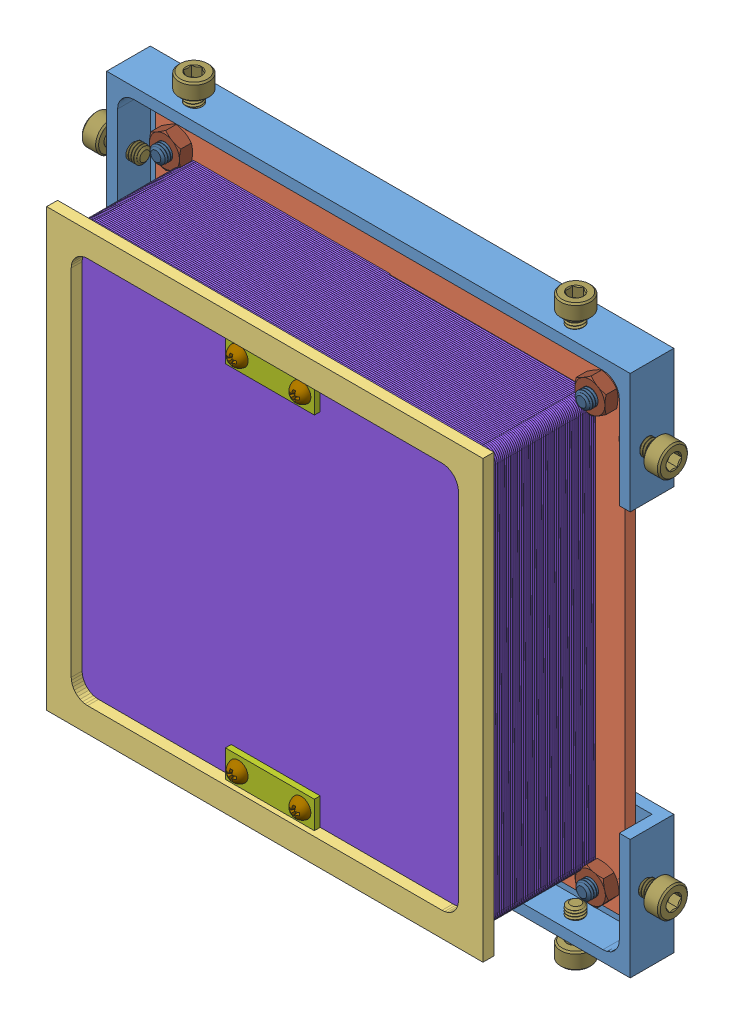
SolidWorks assembly COILS_ASSEMBLY, configuration Default. Lengths in mm.
Overall size (106.29 106.29 30.72).
43 component instances, 12 part files, 22 mates.
Components (placement in the parent):
- STANDARD_MOUNTING_BRACKET_COILS-1: STANDARD_MOUNTING_BRACKET_COILS [Default] at (52.6905 12.4661 89.2142) size (96 96 8)
- Full_MT_Assembly-1: Full_MT_Assembly [Default] at (87.0641 56.7594 26.9574) x (-1 0 0) z (0 0 1) size (86 86 25.67)
  - AirCoreBase-2: AirCoreBase [Default] at (-9.6264 88.2933 66.2568) x (1 0 0) z (0 -1 0) size (86 2.09 86)
  - AirCoreSide-2: AirCoreSide [Default] at (-9.6264 88.2933 64.2568) x (1 0 0) z (0 -1 0) size (80 23.15 80)
  - RodHat_v4-2: RodHat_v4 [Default] at (34.3736 13.7933 80.8268) x (1 0 0) z (0 1 0) size (16.31 5.11 5)
  - RodHat_v4-3: RodHat_v4 [Default] at (34.3736 79.7933 80.8268) x (1 0 0) z (0 1 0) size (16.31 5.11 5)
  - RodHat_v4-4: RodHat_v4 [Default] at (64.8736 44.2933 70.7568) x (0 1 0) z (-1 0 0) size (16.31 5.11 5)
  - RodHat_v4-5: RodHat_v4 [Default] at (-1.1263 44.2933 70.7568) x (0 1 0) z (-1 0 0) size (16.31 5.11 5)
  - Rod_Spiral_Assembly-1: Rod_Spiral_Assembly [Default] at (34.3736 8.7933 83.3268) size (8.7 71 7.53)
    - TorqueRod-1: TorqueRod [Default] at origin size (6.73 71 6.73)
    - RodSpiral-1: RodSpiral [Default] at (0 66 0) x (0 0 1) z (0 -1 0) size (7.53 8.7 61.32)
  - Rod_Spiral_Assembly-3: Rod_Spiral_Assembly [Default] at (69.8736 44.2933 73.2568) x (0 0 1) z (0 -1 0) size (8.7 71 7.53)
    - TorqueRod-1: TorqueRod [Default] at origin size (6.73 71 6.73)
    - RodSpiral-1: RodSpiral [Default] at (0 66 0) x (0 0 1) z (0 -1 0) size (7.53 8.7 61.32)
  - RodHatTop-1: RodHatTop [Default] at (34.3736 8.7933 85.8268) x (1 0 0) z (0 -1 0) size (16.31 5 5)
  - RodHatTop-3: RodHatTop [Default] at (3.8737 44.2933 75.7568) x (0 1 0) z (1 0 0) size (16.31 5 5)
  - RodHatTop-4: RodHatTop [Default] at (69.8736 44.2933 75.7568) x (0 1 0) z (1 0 0) size (16.31 5 5)
  - RodHatTop-5: RodHatTop [Default] at (34.3736 79.7933 85.8268) x (-1 0 0) z (0 1 0) size (16.31 5 5)
  - AirCoreSpiral-1: AirCoreSpiral [Default] at (34.3736 44.2933 66.2568) size (75.7 75.86 21.34)
  - round head screw_ai-1: round head screw_ai [CR-RHMS 0.073-72x0.125x0.125-N] at (40.1286 11.2933 89.8762) x (0 0 -1) z (1 0 0) size (4.68 3.51 3.51)
  - round head screw_ai-4: round head screw_ai [CR-RHMS 0.073-72x0.125x0.125-N] at (28.6186 11.2933 89.8762) x (0 0 -1) z (1 0 0) size (4.68 3.51 3.51)
  - round head screw_ai-5: round head screw_ai [CR-RHMS 0.073-72x0.125x0.125-N] at (1.3737 38.5383 79.8062) x (0 0 -1) z (1 0 0) size (4.68 3.51 3.51)
  - round head screw_ai-6: round head screw_ai [CR-RHMS 0.073-72x0.125x0.125-N] at (1.3737 50.0483 79.8062) x (0 0 -1) z (1 0 0) size (4.68 3.51 3.51)
  - round head screw_ai-7: round head screw_ai [CR-RHMS 0.073-72x0.125x0.125-N] at (28.6186 77.2933 89.8762) x (0 0 -1) z (1 0 0) size (4.68 3.51 3.51)
  - round head screw_ai-8: round head screw_ai [CR-RHMS 0.073-72x0.125x0.125-N] at (40.1286 77.2933 89.8762) x (0 0 -1) z (1 0 0) size (4.68 3.51 3.51)
  - round head screw_ai-10: round head screw_ai [CR-RHMS 0.073-72x0.125x0.125-N] at (67.3736 50.0483 79.8062) x (0 0 -1) z (1 0 0) size (4.68 3.51 3.51)
  - round head screw_ai-11: round head screw_ai [CR-RHMS 0.073-72x0.125x0.125-N] at (67.3736 38.5383 79.8062) x (0 0 -1) z (1 0 0) size (4.68 3.51 3.51)
- M3_8mm_SCREW-1: M3_8mm_SCREW [91292A112] at (91.7793 -26.3643 97.2142) x (0.2404 0.970674 0) z (0 0 1) size (5.5 5.5 11.2)
- M3_8mm_SCREW-2: M3_8mm_SCREW [91292A112] at (13.4924 -26.7684 97.2142) x (0.228314 -0.973588 0) z (0 0 1) size (5.5 5.5 11.2)
- M3_8mm_SCREW-3: M3_8mm_SCREW [91292A112] at (13.6905 51.4661 97.2142) x (0.527737 0.849408 0) z (0 0 1) size (5.5 5.5 11.2)
- M3_8mm_SCREW-4: M3_8mm_SCREW [91292A112] at (91.6905 51.4661 97.2142) size (5.5 5.5 11.2)
- M3_NUT-1: M3_NUT [91828A211] at (13.4924 -26.7684 94.4142) size (5.5 6.35 2.78)
- M3_NUT-2: M3_NUT [91828A211] at (91.7793 -26.3643 94.4142) x (0.958223 0.286022 0) z (0 0 1) size (5.5 6.35 2.78)
- M3_NUT-3: M3_NUT [91828A211] at (13.6905 51.4661 94.4142) size (5.5 6.35 2.78)
- M3_NUT-4: M3_NUT [91828A211] at (91.6905 51.4661 94.4142) size (5.5 6.35 2.78)
- M3_6MM_91292A111_TYPE 18-8 SS SOCKET HEAD CAP SCREW-1: M3_6MM_91292A111_TYPE 18-8 SS SOCKET HEAD CAP SCREW [91292A111] at (87.6905 56.4661 94.2142) x (0.999714 0 -0.023906) z (0 -1 0) size (5.5 5.5 9.19)
- M3_6MM_91292A111_TYPE 18-8 SS SOCKET HEAD CAP SCREW-2: M3_6MM_91292A111_TYPE 18-8 SS SOCKET HEAD CAP SCREW [91292A111] at (96.6905 47.4661 94.2142) x (0 0.999714 -0.023906) z (-1 0 0) size (5.5 5.5 9.19)
- M3_6MM_91292A111_TYPE 18-8 SS SOCKET HEAD CAP SCREW-3: M3_6MM_91292A111_TYPE 18-8 SS SOCKET HEAD CAP SCREW [91292A111] at (17.6905 56.4661 94.2142) x (-0.999714 0 -0.023906) z (0 -1 0) size (5.5 5.5 9.19)
- M3_6MM_91292A111_TYPE 18-8 SS SOCKET HEAD CAP SCREW-4: M3_6MM_91292A111_TYPE 18-8 SS SOCKET HEAD CAP SCREW [91292A111] at (96.6905 -22.5339 94.2142) x (0 -0.999714 -0.023906) z (-1 0 0) size (5.5 5.5 9.19)
- M3_6MM_91292A111_TYPE 18-8 SS SOCKET HEAD CAP SCREW-5: M3_6MM_91292A111_TYPE 18-8 SS SOCKET HEAD CAP SCREW [91292A111] at (87.6905 -31.5339 94.2142) x (0.999714 0 -0.023906) z (0 1 0) size (5.5 5.5 9.19)
- M3_6MM_91292A111_TYPE 18-8 SS SOCKET HEAD CAP SCREW-6: M3_6MM_91292A111_TYPE 18-8 SS SOCKET HEAD CAP SCREW [91292A111] at (17.6905 -31.5339 94.2142) x (-0.999714 0 -0.023906) z (0 1 0) size (5.5 5.5 9.19)
- M3_6MM_91292A111_TYPE 18-8 SS SOCKET HEAD CAP SCREW-7: M3_6MM_91292A111_TYPE 18-8 SS SOCKET HEAD CAP SCREW [91292A111] at (8.6905 -22.5339 94.2142) x (0 -0.999714 -0.023906) z (1 0 0) size (5.5 5.5 9.19)
- M3_6MM_91292A111_TYPE 18-8 SS SOCKET HEAD CAP SCREW-8: M3_6MM_91292A111_TYPE 18-8 SS SOCKET HEAD CAP SCREW [91292A111] at (8.6905 47.4661 94.2142) x (0 0.999714 -0.023906) z (1 0 0) size (5.5 5.5 9.19)
Mates (geometry in assembly coordinates):
- Concentric4: concentric aligned: circle of STANDARD_MOUNTING_BRACKET_COILS-1; circle of Full_MT_Assembly-1/AirCoreBase-2
- Coincident5: coincident anti-aligned: plane of STANDARD_MOUNTING_BRACKET_COILS-1 through (52.6905 12.4661 91.2142) normal (0 0 1); plane of Full_MT_Assembly-1/AirCoreBase-2 through (96.6905 -31.5339 91.2142) normal (0 0 -1)
- Concentric5: concentric aligned: cylinder of STANDARD_MOUNTING_BRACKET_COILS-1 through (91.6905 51.4661 91.2142) axis (0 0 1) radius 1.5; cylinder of Full_MT_Assembly-1/AirCoreBase-2 through (91.6905 51.4661 93.2142) axis (0 0 1) radius 1.25
- Concentric6: concentric aligned: cylinder of STANDARD_MOUNTING_BRACKET_COILS-1 through (13.6905 51.4661 91.2142) axis (0 0 1) radius 1.5; cylinder of Full_MT_Assembly-1/AirCoreBase-2 through (13.6905 51.4661 93.2142) axis (0 0 1) radius 1.25
- Concentric7: concentric aligned: cylinder of STANDARD_MOUNTING_BRACKET_COILS-1 through (13.6905 -26.5339 91.2142) axis (0 0 1) radius 1.5; cylinder of Full_MT_Assembly-1/AirCoreBase-2 through (13.6905 -26.5339 93.2142) axis (0 0 1) radius 1.25
- Tangent1: tangent: curve of STANDARD_MOUNTING_BRACKET_COILS-1; curve of M3_8mm_SCREW-1
- Coincident6: coincident anti-aligned: plane of STANDARD_MOUNTING_BRACKET_COILS-1 through (52.6905 12.4661 89.2142) normal (0 0 -1); plane of M3_8mm_SCREW-1 through (91.7793 -26.3643 89.2142) normal (0 0 1)
- Concentric8: concentric anti-aligned: cylinder of M3_8mm_SCREW-1 through (91.7793 -26.3643 89.2142) axis (0 0 1) radius 1.5; cylinder of M3_NUT-2 through (91.7793 -26.3643 95.6142) axis (0 0 -1) radius 1.5
- Coincident7: coincident anti-aligned: plane of Full_MT_Assembly-1/AirCoreBase-2 through (96.6905 -31.5339 93.2142) normal (0 0 1); plane of M3_NUT-2 through (88.6901 -25.6295 93.2142) normal (0 0 -1)
- Tangent5: tangent: circle of STANDARD_MOUNTING_BRACKET_COILS-1; curve of M3_8mm_SCREW-2
- Coincident9: coincident anti-aligned: plane of STANDARD_MOUNTING_BRACKET_COILS-1 through (52.6905 12.4661 89.2142) normal (0 0 -1); plane of M3_8mm_SCREW-2 through (13.4924 -26.7684 89.2142) normal (0 0 1)
- Concentric9: concentric anti-aligned: cylinder of M3_8mm_SCREW-2 through (13.4924 -26.7684 89.2142) axis (0 0 1) radius 1.5; cylinder of M3_NUT-1 through (13.4924 -26.7684 95.6142) axis (0 0 -1) radius 1.5
- Coincident10: coincident anti-aligned: plane of Full_MT_Assembly-1/AirCoreBase-2 through (96.6905 -31.5339 93.2142) normal (0 0 1); plane of M3_NUT-1 through (10.7424 -25.1807 93.2142) normal (0 0 -1)
- Concentric10: concentric anti-aligned: cylinder of M3_8mm_SCREW-3 through (13.6905 51.4661 89.2142) axis (0 0 1) radius 1.5; cylinder of M3_NUT-3 through (13.6905 51.4661 95.6142) axis (0 0 -1) radius 1.5
- Coincident11: coincident anti-aligned: plane of Full_MT_Assembly-1/AirCoreBase-2 through (96.6905 -31.5339 93.2142) normal (0 0 1); plane of M3_NUT-3 through (10.9405 53.0538 93.2142) normal (0 0 -1)
- Concentric11: concentric anti-aligned: circle of STANDARD_MOUNTING_BRACKET_COILS-1; circle of M3_8mm_SCREW-3
- Concentric12: concentric anti-aligned: circle of STANDARD_MOUNTING_BRACKET_COILS-1; circle of M3_8mm_SCREW-4
- Coincident12: coincident anti-aligned: plane of STANDARD_MOUNTING_BRACKET_COILS-1 through (52.6905 12.4661 89.2142) normal (0 0 -1); plane of M3_8mm_SCREW-4 through (91.6905 51.4661 89.2142) normal (0 0 1)
- Concentric13: concentric anti-aligned: cylinder of M3_8mm_SCREW-4 through (91.6905 51.4661 89.2142) axis (0 0 1) radius 1.5; cylinder of M3_NUT-4 through (91.6905 51.4661 95.6142) axis (0 0 -1) radius 1.5
- Coincident13: coincident anti-aligned: plane of Full_MT_Assembly-1/AirCoreBase-2 through (96.6905 -31.5339 93.2142) normal (0 0 1); plane of M3_NUT-4 through (88.9405 53.0538 93.2142) normal (0 0 -1)
- Concentric14: concentric anti-aligned: circle of STANDARD_MOUNTING_BRACKET_COILS-1; circle of M3_6MM_91292A111_TYPE 18-8 SS SOCKET HEAD CAP SCREW-1
- Distance1: distance = 2 mm anti-aligned: plane of STANDARD_MOUNTING_BRACKET_COILS-1 through (4.6905 60.4661 97.2142) normal (0 1 0); plane of M3_6MM_91292A111_TYPE 18-8 SS SOCKET HEAD CAP SCREW-1 through (87.6905 62.4661 94.2142) normal (0 -1 0)
